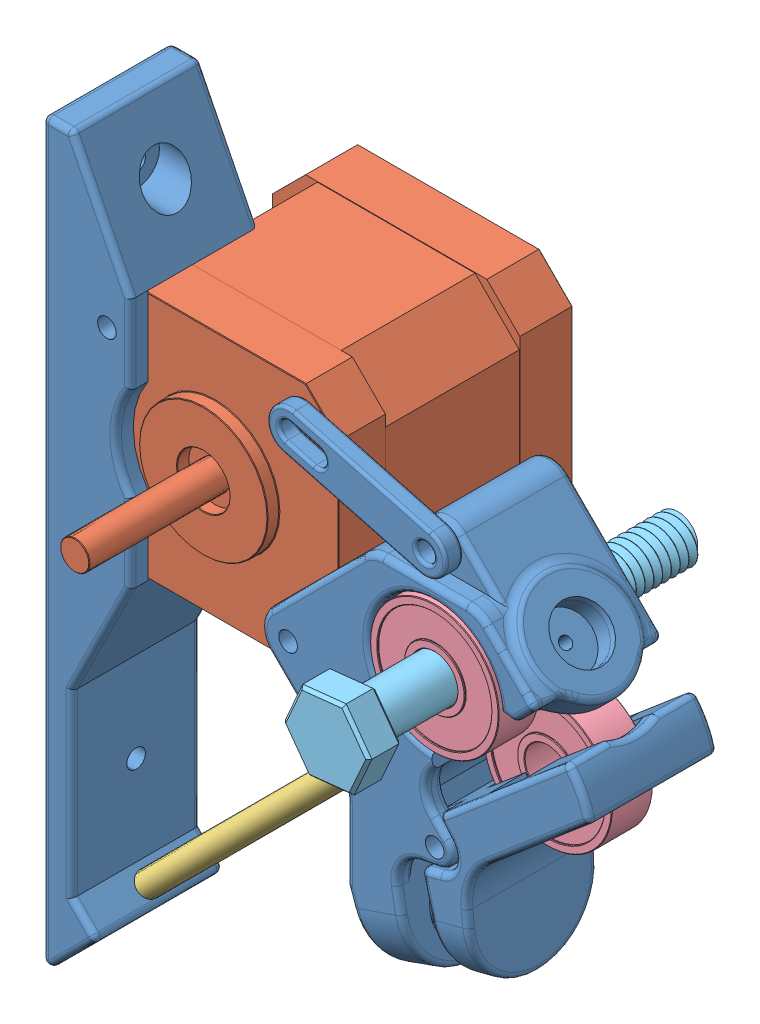
SolidWorks assembly assembled_extruder_hobbed, configuration Default. Lengths in mm.
Overall size (167.01 128.3 64).
10 component instances, 5 part files, 25 mates.
Components (placement in the parent):
- extruder_hobbed-4: extruder_hobbed [Body] x (-0.707107 -0.707107 0) z (0 0 1) size (59.39 49.07 22.17)
- extruder_hobbed-5: extruder_hobbed [Idler] at (2.0403 -0.079 0) x (-0.762516 -0.646969 0) z (0 0 1) size (44.83 23.9 22)
- extruder_hobbed-6: extruder_hobbed [Motor Arm] x (-0.707107 -0.707107 0) z (0 0 1) size (19.32 28.12 3)
- nema_17_steppermotor-2: nema_17_steppermotor [Default] at (-40.5187 8.4966 -32) x (0 -1 0) z (-1 0 0) size (42.3 64 42.3)
- extruder_hobbed-7: extruder_hobbed [Mount] x (-0.707107 -0.707107 0) z (0 0 1) size (91.91 89.52 22.06)
- bowden_tube-1: bowden_tube [Default] at (-7.5715 -13.5041 0) x (0.5 -0.5 0.707107) z (-0.707107 -0.707107 0) size (4 4 79)
- bearing_22x7-4: bearing_22x7 [Default] at (0 0 7.5) size (22 22 7)
- bearing_22x7-5: bearing_22x7 [Default] at (0 0 -7.5) size (22 22 7)
- bearing_22x7-6: bearing_22x7 [Default] at (11.871 -11.6654 0) size (22 22 7)
- hobbed_bolt_m8-2: hobbed_bolt_m8 [Default] at (0 0 23.9946) x (-0.405983 -0.91388 0) z (-0.91388 0.405983 0) size (14.91 61.47 12.91)
Mates (geometry in assembly coordinates):
- Parallel1: parallel: plane of extruder_hobbed-4 through (-15.0187 -37.9567 -4) normal (-1 0 0); plane of assembly through (0 0 0) normal (1 0 0)
- Coincident2: coincident: plane of ? through (0 0 0) normal (0 0 1)
- Coincident3: coincident: line of ? through (-12.1917 0 0) axis (0 0.707107 -0.707107)
- Coincident4: coincident: line of ? through (-26.9893 0 0) axis (0 -0.707107 -0.707107)
- Concentric1: concentric anti-aligned: cylinder of extruder_hobbed-4 through (0.0548 -24.9697 8) axis (0 0 1) radius 1.6; cylinder of extruder_hobbed-5 through (0.0548 -24.9697 61.8936) axis (0 0 -1) radius 1.6
- Coincident5: coincident aligned: plane of extruder_hobbed-5 through (2.0403 -0.079 0) normal (0 0 1); plane of assembly through (0 0 0) normal (0 0 1)
- Concentric2: concentric aligned: cylinder of extruder_hobbed-4 through (-1.6538 17.7758 -11) axis (0 0 1) radius 1.6; cylinder of extruder_hobbed-6 through (-1.6538 17.7758 -26.1192) axis (0 0 1) radius 1.6
- Coincident6: coincident aligned: plane of extruder_hobbed-6 through (0 0 0) normal (0 0 1); plane of assembly through (0 0 0) normal (0 0 1)
- Coincident7: coincident anti-aligned: plane of extruder_hobbed-4 through (-25.0187 -7.0034 8) normal (0 0 -1); plane of nema_17_steppermotor-2 through (-40.5187 8.4966 8) normal (0 0 1)
- Concentric3: concentric anti-aligned: cylinder of extruder_hobbed-4 through (-25.0187 -7.0034 8) axis (0 0 1) radius 1.6; cylinder of nema_17_steppermotor-2 through (-25.0187 -7.0034 -23) axis (0 0 -1) radius 1.5
- Parallel2: parallel aligned: plane of extruder_hobbed-4 through (-15.0187 -37.9567 -4) normal (-1 0 0); plane of nema_17_steppermotor-2 through (-61.5687 21.9753 0) normal (-1 0 0)
- Tangent4: tangent: plane of extruder_hobbed-6 through (-24.6071 25.5428 -26.1192) normal (-0.257283 -0.966336 0); circle of nema_17_steppermotor-2
- Coincident12: coincident anti-aligned: plane of nema_17_steppermotor-2 through (-40.5187 8.4966 8) normal (0 0 1); plane of extruder_hobbed-7 through (-40.5187 8.4966 8) normal (0 0 -1)
- Concentric8: concentric aligned: cylinder of nema_17_steppermotor-2 through (-56.0187 23.9966 -23) axis (0 0 -1) radius 1.5; cylinder of extruder_hobbed-7 through (-56.0187 23.9966 140.7147) axis (0 0 -1) radius 1.6
- Parallel5: parallel aligned: cylinder of nema_17_steppermotor-2 through (-56.0187 -7.0034 -23) axis (0 0 -1) radius 1.5; cylinder of extruder_hobbed-7 through (-56.0187 -7.0034 140.7147) axis (0 0 -1) radius 1.6
- Concentric10: concentric aligned: cylinder of nema_17_steppermotor-2 through (-56.0187 -7.0034 -23) axis (0 0 -1) radius 1.5; cylinder of extruder_hobbed-7 through (-56.0187 -7.0034 140.7147) axis (0 0 -1) radius 1.6
- Coincident13: coincident anti-aligned: plane of extruder_hobbed-7 through (-63.4329 -69.3656 0) normal (0.707107 0.707107 0); plane of bowden_tube-1 through (-63.4329 -69.3656 0) normal (-0.707107 -0.707107 0)
- Concentric11: concentric aligned: cylinder of extruder_hobbed-7 through (-69.14 -75.0727 0) axis (0.707107 0.707107 0) radius 1.125; cylinder of bowden_tube-1 through (-63.4329 -69.3656 0) axis (0.707107 0.707107 0) radius 1
- Concentric12: concentric aligned: cylinder of extruder_hobbed-4 through (0 0 -4) axis (0 0 1) radius 4.15; cylinder of bearing_22x7-4 through (0 0 4) axis (0 0 1) radius 3.95
- Coincident14: coincident anti-aligned: plane of extruder_hobbed-4 through (0.0548 -24.9697 4) normal (0 0 1); plane of bearing_22x7-4 through (0 0 4) normal (0 0 -1)
- Concentric13: concentric aligned: cylinder of extruder_hobbed-4 through (0 0 -4) axis (0 0 1) radius 4.15; cylinder of bearing_22x7-5 through (0 0 -11) axis (0 0 1) radius 3.95
- Coincident15: coincident anti-aligned: plane of extruder_hobbed-4 through (0.0548 -24.9697 -4) normal (0 0 -1); plane of bearing_22x7-5 through (0 0 -4) normal (0 0 1)
- Concentric15: concentric aligned: cylinder of extruder_hobbed-5 through (11.871 -11.6654 -61.8936) axis (0 0 1) radius 3.9; cylinder of bearing_22x7-6 through (11.871 -11.6654 -3.5) axis (0 0 1) radius 3.95
- Coincident16: coincident aligned: plane of bearing_22x7-6 through (11.871 -11.6654 0) normal (0 0 1); plane of assembly through (0 0 0) normal (0 0 1)
- Concentric16: concentric aligned: cylinder of bearing_22x7-4 through (0 0 4) axis (0 0 1) radius 3.95; cylinder of hobbed_bolt_m8-2 through (0 0 -31.0054) axis (0 0 1) radius 3.9
